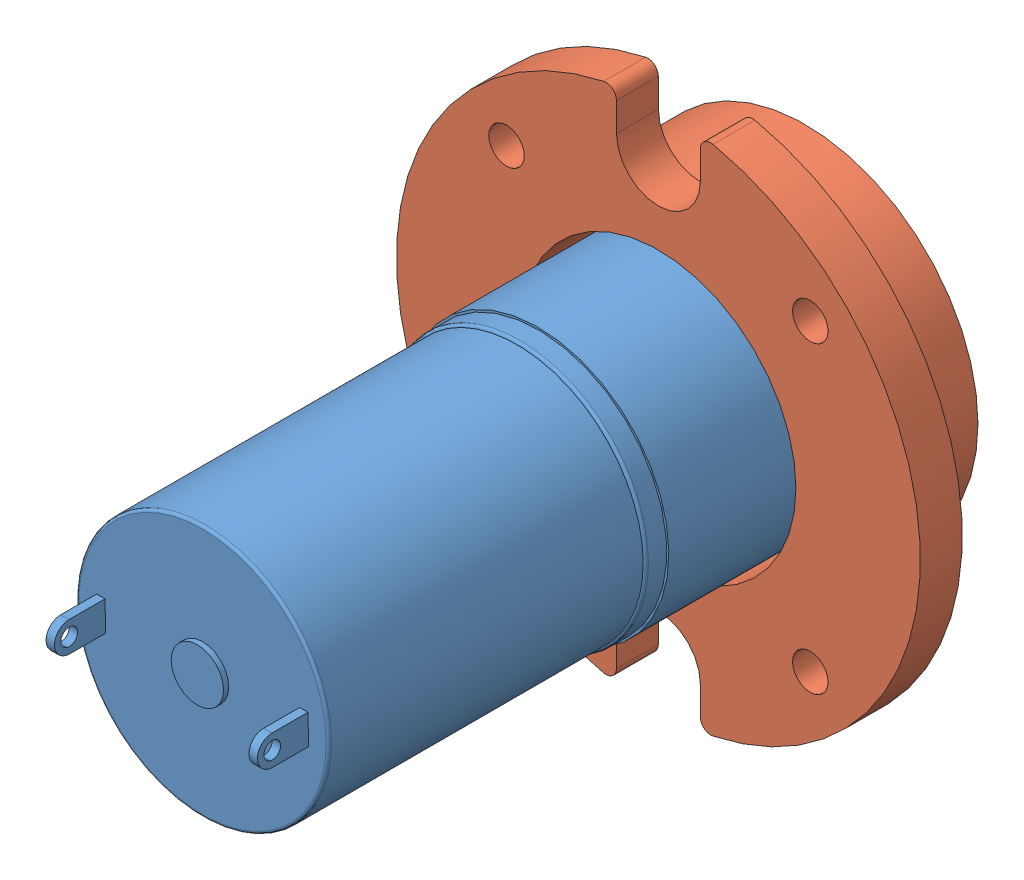
SolidWorks assembly Side_Assem, configuration Default. Lengths in mm.
Overall size (175 49.29 71.85).
4 component instances, 3 part files, 3 mates.
Components (placement in the parent):
- 25x55_gear_motor-1: 25x55_gear_motor [Default] at (54.7538 17.915 -14.1243) x (-0.999873 -0.015933 0) z (0 0 -1) size (25 25 71.85)
- 25x55_gear_motor-3: 25x55_gear_motor [Default] at (-70.2462 17.915 -14.1243) x (-0.999873 -0.015933 0) z (0 0 -1) size (25 25 71.85) (hidden)
- motor_holder_r0.5-1: motor_holder_r0.5 [Default] at (54.7538 17.915 -4.6243) x (0 0 -1) z (1 0 0) size (14 48.95 50)
- motor_holder_fr0.6-1: motor_holder_fr0.6 [Default] at (-70.2462 17.915 -4.6243) x (0 0 -1) z (1 0 0) size (14 49.29 50) (hidden)
Mates (geometry in assembly coordinates):
- Coincident3: coincident aligned: plane of 25x55_gear_motor-1 through (54.7538 17.915 -16.1243) normal (0 0 -1); plane of 25x55_gear_motor-3 through (-70.2462 17.915 -16.1243) normal (0 0 -1)
- Concentric2: concentric anti-aligned: cylinder of 25x55_gear_motor-1 through (54.7538 17.915 6.8757) axis (0 0 -1) radius 12.5; cylinder of motor_holder_r0.5-1 through (54.7538 17.915 -18.6243) axis (0 0 1) radius 16.5
- Concentric5: concentric anti-aligned: cylinder of 25x55_gear_motor-3 through (-70.2462 17.915 6.8757) axis (0 0 -1) radius 12.5; cylinder of motor_holder_fr0.6-1 through (-70.2462 17.915 -18.6243) axis (0 0 1) radius 16.5
